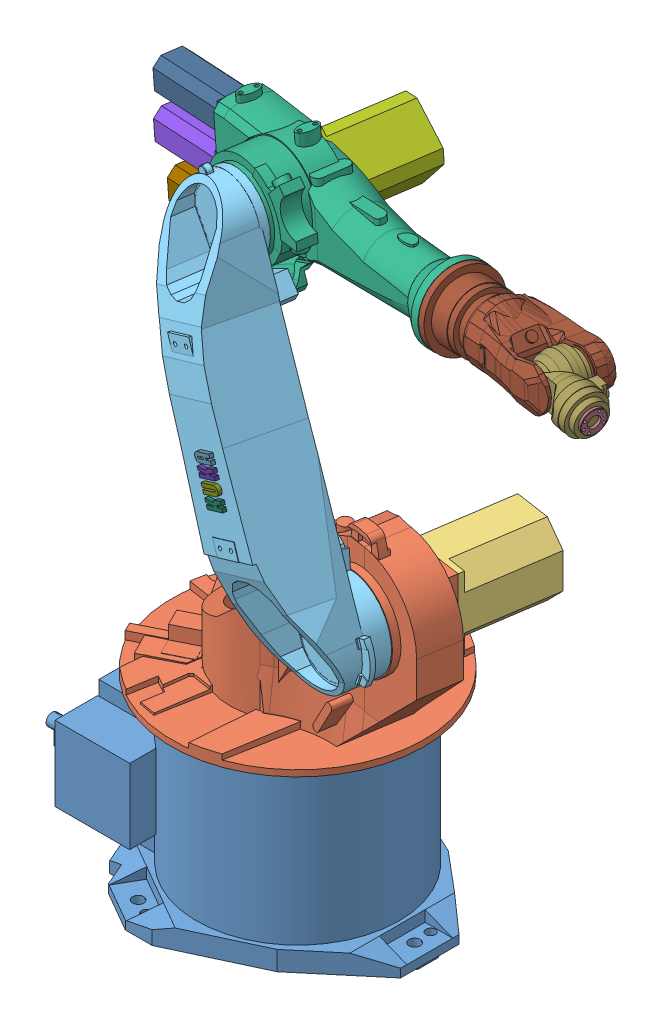
SolidWorks assembly KUKA_KR6, configuration Varsayılan. Lengths in mm.
Overall size (1189.72 1459.85 638.99).
17 component instances, 17 part files, 46 mates.
Components (placement in the parent):
- KUKA_Base-1: KUKA_Base [Varsayılan] x (1 0 0) z (0 1 0) size (684.31 536 396.92)
- KUKA_L1-1: KUKA_L1 [Varsayılan] x (0.988987 0 0.148004) z (0 1 0) size (663 540 461.9)
- KUKA_A2-1: KUKA_A2 [Varsayılan] at (-0.1429 -0.1804 -0.0256) x (0.988987 0 0.148004) z (0 1 0) size (155 197.5 155)
- KUKA_A1-1: KUKA_A1 [Varsayılan] at (-0.1169 0.0077 -0.1999) x (0.988987 0 0.148004) z (0 1 0) size (155 155 197.5)
- KUKA_L2-1: KUKA_L2 [Varsayılan] at (265.0289 -48.2989 39.6622) x (0.918912 0.369715 0.137517) z (-0.365644 0.929145 -0.054719) size (219.37 199.5 863.7)
- KUKA_L3-1: KUKA_L3 [Varsayılan] at (-118.8914 -66.8747 -17.7924) x (0.984425 0.095935 0.147322) z (-0.094878 0.995388 -0.014199) size (561.5 195.5 287.5)
- KUKA_A3-1: KUKA_A3 [Varsayılan] at (-118.8914 -66.8747 -17.7924) x (0.984425 0.095935 0.147322) z (-0.094878 0.995388 -0.014199) size (178.69 177 178.69)
- KUKA_A4-1: KUKA_A4 [Varsayılan] at (-48.7654 1247.0356 -1341.9959) x (0.984425 0.095935 0.147322) z (-0.148004 0 0.988987) size (170 72.5 72.5)
- KUKA_A5-1: KUKA_A5 [Varsayılan] at (-53.6769 1155.012 -1249.2514) x (0.984425 0.095935 0.147322) z (-0.148004 0 0.988987) size (170 72.5 72.5)
- KUKA_A6-1: KUKA_A6 [Varsayılan] at (-43.816 1339.059 -1434.9937) x (0.984425 0.095935 0.147322) z (-0.148004 0 0.988987) size (170 72.5 72.5)
- KUKA_L4-1: KUKA_L4 [Varsayılan] at (-361.256 2559.844 -108.7798) x (0.984425 0.095935 0.147322) z (0.088731 -0.994551 0.054731) size (312.22 155 155)
- KUKA_L5-1: KUKA_L5 [Varsayılan] at (-381.7817 114.7689 17.4489) x (0.983142 -0.09684 0.15509) z (0.101965 0.994463 -0.025421) size (157.3 101 97)
- KUKA_L6-1: KUKA_L6 [Varsayılan] at (-10.7695 1875.5561 -1235.007) x (0.983142 -0.09684 0.15509) z (-0.179105 -0.339467 0.923409) size (6.2 50 50)
- KUKA_KR6-Part-2-1: KUKA_KR6-Part-2 [Varsayılan] at (1649.5214 648.8401 453.6321) x (-0.365644 0.929145 -0.054719) z (-0.918912 -0.369715 -0.137517) size (18.86 8 42.12)
- KUKA_KR6-Part-3-1: KUKA_KR6-Part-3 [Varsayılan] at (1666.2535 606.3216 456.1361) x (-0.365644 0.929145 -0.054719) z (-0.918912 -0.369715 -0.137517) size (18.99 8 42.12)
- KUKA_KR6-Part-4-1: KUKA_KR6-Part-4 [Varsayılan] at (1645.6392 658.7052 453.0512) x (-0.365644 0.929145 -0.054719) z (-0.918912 -0.369715 -0.137517) size (18.86 8 42.12)
- KUKA_KR6-Part-16-1: KUKA_KR6-Part-16 [Varsayılan] at (1624.5485 712.2991 449.8949) x (-0.365644 0.929145 -0.054719) z (-0.918912 -0.369715 -0.137517) size (18.99 8 42.12)
Mates (geometry in assembly coordinates):
- Çakışık2: coincident: plane of KUKA_Base-1 through (0 0 0) normal (1 0 0); plane of assembly through (0 0 0) normal (1 0 0)
- Çakışık3: coincident: plane of KUKA_Base-1 through (0 0 0) normal (0 1 0); plane of assembly through (0 0 0) normal (0 1 0)
- Çakışık4: coincident: plane of KUKA_Base-1 through (0 0 0) normal (0 0 -1); plane of assembly through (0 0 0) normal (0 0 1)
- Çakışık5: coincident: plane of KUKA_Base-1 through (0 396.9235 0) normal (0 1 0); plane of KUKA_L1-1 through (0 396.9235 0) normal (0 -1 0)
- Eş Merkezli1: concentric: cylinder of KUKA_Base-1 through (0 47.4 0) axis (0 1 0) radius 216.5; cylinder of KUKA_L1-1 through (0 410.1235 0) axis (0 1 0) radius 270
- Çakışık6: coincident: plane of KUKA_A1-1 through (88.1168 447.0035 -65.1761) normal (0 -1 0); plane of KUKA_L1-1 through (65.1761 447.0035 88.1168) normal (0 1 0)
- Çakışık7: coincident: plane of KUKA_A1-1 through (11.4703 459.0035 -76.6465) normal (0.148004 0 -0.988987); plane of KUKA_L1-1 through (-65.1761 409.0035 -88.1168) normal (0.148004 0 -0.988987)
- Çakışık8: coincident: plane of KUKA_A1-1 through (76.6465 459.0035 11.4703) normal (0.988987 0 0.148004); plane of KUKA_L1-1 through (88.1168 409.0035 -65.1761) normal (0.988987 0 0.148004)
- Çakışık9: coincident: plane of KUKA_A2-1 through (341.4792 597.5 -1.4759) normal (-0.148004 0 0.988987); plane of KUKA_L1-1 through (188.1863 597.5 -24.4165) normal (0.148004 0 -0.988987)
- Çakışık10: coincident: plane of KUKA_A2-1 through (343.2553 675 -13.3437) normal (0.988987 0 0.148004); plane of KUKA_L1-1 through (335.8551 597.5 36.1056) normal (0.988987 0 0.148004)
- Çakışık11: coincident: plane of KUKA_A2-1 through (266.6088 597.5 -24.814) normal (0 -1 0); plane of KUKA_L1-1 through (182.5621 597.5 13.165) normal (0 -1 0)
- Çakışık13: coincident: plane of KUKA_L1-1 through (244.8522 675 120.567) normal (-0.148004 0 0.988987); plane of KUKA_L2-1 through (244.8522 675 120.567) normal (0.148004 0 -0.988987)
- Eş Merkezli2: concentric: cylinder of KUKA_L1-1 through (247.2203 675 104.7432) axis (-0.148004 0 0.988987) radius 93.25; cylinder of KUKA_L2-1 through (244.8522 675 120.567) axis (-0.148004 0 0.988987) radius 91
- Çakışık14: coincident: plane of KUKA_L3-1 through (99.7641 1363.3956 133.2328) normal (-0.148004 0 0.988987); plane of KUKA_L2-1 through (79.8525 1391.7688 130.253) normal (0.148004 0 -0.988987)
- Eş Merkezli3: concentric: cylinder of KUKA_L3-1 through (-7.3376 1306.8186 107.0935) axis (-0.148004 0 0.988987) radius 80; cylinder of KUKA_L2-1 through (-7.3376 1306.8186 107.0935) axis (-0.148004 0 0.988987) radius 80
- Çakışık15: coincident: plane of KUKA_L3-1 through (13.6858 1306.9687 -34.3528) normal (0.148004 0 -0.988987); plane of KUKA_A3-1 through (13.6858 1306.9687 -34.3528) normal (-0.148004 0 0.988987)
- Çakışık16: coincident: plane of KUKA_L3-1 through (54.4592 1355.7196 -35.3289) normal (0.629005 0.771682 0.094132); plane of KUKA_A3-1 through (54.4592 1355.7196 -35.3289) normal (0.629005 0.771682 0.094132)
- Çakışık17: coincident: plane of KUKA_L3-1 through (-33.4922 1347.1485 -48.491) normal (-0.763183 0.636009 -0.114212); plane of KUKA_A3-1 through (-33.4922 1347.1485 -48.491) normal (-0.763183 0.636009 -0.114212)
- Çakışık18: coincident: plane of KUKA_L3-1 through (-110.3373 1167.1957 -16.5122) normal (-0.984425 -0.095935 -0.147322); plane of KUKA_A5-1 through (-110.3373 1167.1957 -16.5122) normal (0.984425 0.095935 0.147322)
- Çakışık19: coincident: plane of KUKA_L3-1 through (-145.1961 1256.677 -21.7289) normal (-0.984425 -0.095935 -0.147322); plane of KUKA_A4-1 through (-145.1961 1256.677 -21.7289) normal (0.984425 0.095935 0.147322)
- Çakışık20: coincident: plane of KUKA_L3-1 through (-146.5776 1349.5476 -22.0653) normal (-0.984425 -0.095935 -0.147322); plane of KUKA_A6-1 through (-146.5776 1349.5476 -22.0653) normal (0.984425 0.095935 0.147322)
- Çakışık21: coincident: plane of KUKA_L3-1 through (-156.8649 1349.0679 13.0489) normal (-0.148004 0 0.988987); plane of KUKA_A6-1 through (-156.8649 1349.0679 13.0489) normal (-0.148004 0 0.988987)
- Çakışık22: coincident: plane of KUKA_L3-1 through (-154.939 1385.1507 -23.3166) normal (-0.094878 0.995388 -0.014199); plane of KUKA_A6-1 through (-154.939 1385.1507 -23.3166) normal (-0.094878 0.995388 -0.014199)
- Çakışık23: coincident: plane of KUKA_L3-1 through (-155.4834 1256.1974 13.3852) normal (-0.148004 0 0.988987); plane of KUKA_A4-1 through (-155.4834 1256.1974 13.3852) normal (-0.148004 0 0.988987)
- Çakışık24: coincident: plane of KUKA_L3-1 through (-153.5575 1292.2802 -22.9803) normal (-0.094878 0.995388 -0.014199); plane of KUKA_A4-1 through (-153.5575 1292.2802 -22.9803) normal (-0.094878 0.995388 -0.014199)
- Çakışık25: coincident: plane of KUKA_L3-1 through (-120.6246 1166.7161 18.6019) normal (-0.148004 0 0.988987); plane of KUKA_A5-1 through (-120.6246 1166.7161 18.6019) normal (-0.148004 0 0.988987)
- Çakışık26: coincident: plane of KUKA_L3-1 through (-111.8201 1130.6333 -16.7341) normal (0.094878 -0.995388 0.014199); plane of KUKA_A5-1 through (-111.8201 1130.6333 -16.7341) normal (0.094878 -0.995388 0.014199)
- Çakışık27: coincident: plane of KUKA_L3-1 through (407.5585 1310.5459 60.9921) normal (0.984425 0.095935 0.147322); plane of KUKA_L4-1 through (407.5585 1310.5459 60.9921) normal (-0.984425 -0.095935 -0.147322)
- Eş Merkezli4: concentric: cylinder of KUKA_L3-1 through (-134.8597 1257.6857 -20.1821) axis (-0.984425 -0.095935 -0.147322) radius 78.5; cylinder of KUKA_L4-1 through (403.6208 1310.1622 60.4028) axis (0.984425 0.095935 0.147322) radius 77.5
- Çakışık28: coincident: plane of KUKA_L4-1 through (675.1787 1335.2363 75.785) normal (-0.151769 0.040807 0.987573); plane of KUKA_L5-1 through (675.1787 1335.2363 75.785) normal (0.151769 -0.040807 -0.987573)
- Eş Merkezli5: concentric: cylinder of KUKA_L4-1 through (675.1787 1335.2363 75.785) axis (0.151769 -0.040807 -0.987573) radius 31; cylinder of KUKA_L5-1 through (665.2499 1337.9059 140.392) axis (0.151769 -0.040807 -0.987573) radius 37.5
- Çakışık29: coincident: plane of KUKA_L5-1 through (774.1008 1326.8629 145.0001) normal (0.983142 -0.09684 0.15509); plane of KUKA_L6-1 through (774.1008 1326.8629 145.0001) normal (-0.983142 0.09684 -0.15509)
- Eş Merkezli6: concentric: cylinder of KUKA_L5-1 through (756.1093 1328.6351 142.162) axis (0.983142 -0.09684 0.15509) radius 33.5; cylinder of KUKA_L6-1 through (766.7272 1327.5892 143.837) axis (0.983142 -0.09684 0.15509) radius 25
- Çakışık30: coincident: plane of KUKA_KR6-Part-4-1 through (128.2101 951.9354 297.7549) normal (0.148004 0 -0.988987); plane of KUKA_KR6-Part-16-1 through (111.3506 979.4736 295.2318) normal (0.148004 0 -0.988987)
- Çakışık31: coincident: plane of KUKA_KR6-Part-3-1 through (130.313 931.2879 298.0696) normal (0.148004 0 -0.988987); plane of KUKA_KR6-Part-4-1 through (128.2101 951.9354 297.7549) normal (0.148004 0 -0.988987)
- Çakışık32: coincident: plane of KUKA_KR6-Part-2-1 through (87.873 991.5211 291.7184) normal (0.148004 0 -0.988987); plane of KUKA_KR6-Part-3-1 through (130.313 931.2879 298.0696) normal (0.148004 0 -0.988987)
- Çakışık33: coincident: plane of KUKA_KR6-Part-2-1 through (118.6028 1001.8551 296.3171) normal (0.918912 0.369715 0.137517); plane of KUKA_KR6-Part-3-1 through (145.327 933.9456 300.3165) normal (0.918912 0.369715 0.137517)
- Çakışık34: coincident: plane of KUKA_KR6-Part-3-1 through (149.4647 923.4313 300.9357) normal (0.918912 0.369715 0.137517); plane of KUKA_KR6-Part-16-1 through (130.5023 971.617 298.0979) normal (0.918912 0.369715 0.137517)
- Çakışık35: coincident: plane of KUKA_KR6-Part-3-1 through (106.3921 918.9556 294.4898) normal (-0.918912 -0.369715 -0.137517); plane of KUKA_KR6-Part-4-1 through (101.618 931.0871 293.7753) normal (-0.918912 -0.369715 -0.137517)
- Uzaklık1: distance = 25 mm: plane of KUKA_KR6-Part-4-1 through (131.6582 943.1735 298.2709) normal (0.365644 -0.929145 0.054719); plane of KUKA_KR6-Part-3-1 through (149.4647 923.4313 300.9357) normal (0.365644 -0.929145 0.054719)
- Uzaklık2: distance = 8 mm: plane of KUKA_KR6-Part-4-1 through (124.7621 960.6973 297.2389) normal (-0.365644 0.929145 -0.054719); plane of KUKA_KR6-Part-16-1 through (130.5023 971.617 298.0979) normal (0.365644 -0.929145 0.054719)
- Uzaklık3: distance = 25 mm: plane of KUKA_KR6-Part-16-1 through (130.5023 971.617 298.0979) normal (0.365644 -0.929145 0.054719); plane of KUKA_KR6-Part-2-1 through (91.3211 982.7592 292.2344) normal (0.365644 -0.929145 0.054719)
- Çakışık36: coincident: plane of KUKA_L2-1 through (216.3614 675 310.9469) normal (-0.148004 0 0.988987); plane of KUKA_KR6-Part-3-1 through (130.313 931.2879 298.0696) normal (0.148004 0 -0.988987)
- Paralel3: parallel: plane of KUKA_L2-1 through (114.45 855.5306 295.6957) normal (-0.365644 0.929145 -0.054719); plane of KUKA_KR6-Part-3-1 through (149.4647 923.4313 300.9357) normal (0.365644 -0.929145 0.054719)
- Çakışık37: coincident: plane of KUKA_L2-1 through (167.7469 876.974 303.6717) normal (0.918912 0.369715 0.137517); plane of KUKA_KR6-Part-3-1 through (145.327 933.9456 300.3165) normal (0.918912 0.369715 0.137517)
- Uzaklık4: distance = 50 mm: plane of KUKA_L2-1 through (114.45 855.5306 295.6957) normal (-0.365644 0.929145 -0.054719); plane of KUKA_KR6-Part-3-1 through (149.4647 923.4313 300.9357) normal (0.365644 -0.929145 0.054719)
